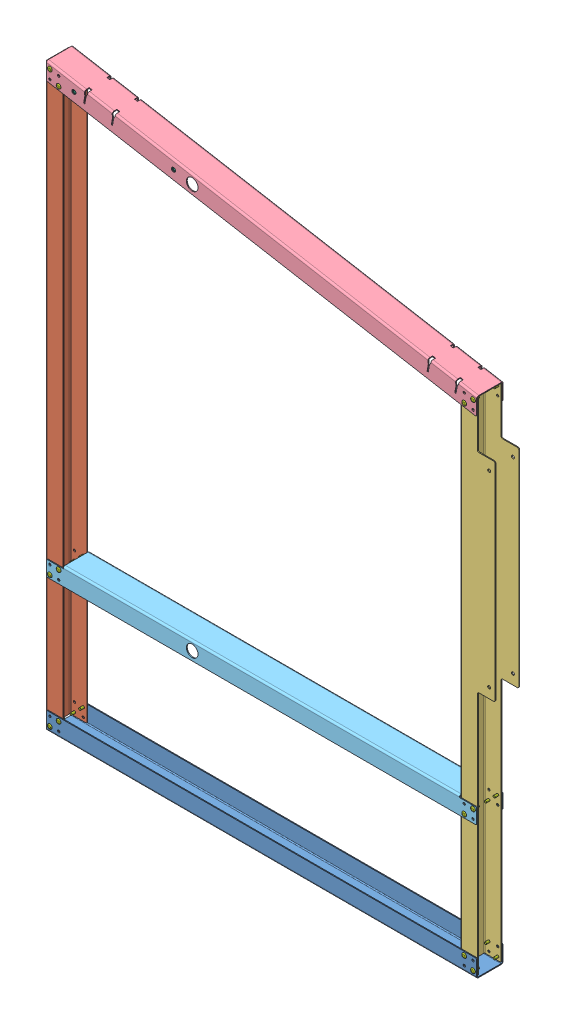
SolidWorks assembly GE-22001, configuration Default. Lengths in mm.
Overall size (976.07 1257.64 60.35).
33 component instances, 7 part files, 66 mates.
Components (placement in the parent):
- GE-22001-01-1: GE-22001-01 [Default] at origin size (932.18 38.1 57.15)
- GE-22001-02-1: GE-22001-02 [Default] at (-469.9 626.8796 0) x (0 0 1) z (-1 0 0) size (53.36 1249.93 38.1)
- GE-22001-03-2: GE-22001-03 [Default] at (427.99 548.0126 0) x (0 0 1) z (-1 0 0) size (53.36 1092.2 76.2)
- GE-22001-04-1: GE-22001-04 [Default] at (0.8773 1173.5467 0) x (0 0 -1) z (0.173648 0.984808 0) size (57.15 952.05 38.1)
- GE-22001-05-1: GE-22001-05 [Default] at (0 322.5952 0) x (1 0 0) z (0 0 -1) size (932.18 38.1 57.15)
- pem_clinchnut_.25_20_.054-1: pem_clinchnut_.25_20_.054 [Default] at (-190.6532 1187.9748 27.3634) x (0 0 -1) z (1 0 0) size (5.69 11.18 11.18)
- pem_clinchnut_.25_20_.054-2: pem_clinchnut_.25_20_.054 [Default] at (-406.4 1226.0168 27.3634) x (0 0 -1) z (0.987351 0.158553 0) size (5.69 11.18 11.18)
- pem_clinchnut_.25_20_.054-4: pem_clinchnut_.25_20_.054 [Default] at (-190.6532 1187.9748 -27.3634) x (0 0 1) z (-0.959125 0.282984 0) size (5.69 11.18 11.18)
- pem_clinchnut_.25_20_.054-6: pem_clinchnut_.25_20_.054 [Default] at (-406.4 1226.0168 -27.3634) x (0 0 1) z (-0.928571 0.371154 0) size (5.69 11.18 11.18)
- rivet_.1875_.126-.25-1: rivet_.1875_.126-.25 [Default] at (458.47 9.5326 28.575) size (10.01 10.01 13.03)
- rivet_.1875_.126-.25-2: rivet_.1875_.126-.25 [Default] at (439.42 28.5826 28.575) x (0.987351 0.158553 0) z (0 0 1) size (10.01 10.01 13.03)
- rivet_.1875_.126-.25-4: rivet_.1875_.126-.25 [Default] at (-458.47 9.5326 28.575) x (0.959125 0.282984 0) z (0 0 1) size (10.01 10.01 13.03)
- rivet_.1875_.126-.25-6: rivet_.1875_.126-.25 [Default] at (-439.42 28.5826 28.575) x (0.928571 0.371154 0) z (0 0 1) size (10.01 10.01 13.03)
- rivet_.1875_.126-.25-8: rivet_.1875_.126-.25 [Default] at (-458.47 294.0126 28.575) x (0.642788 0.766044 0) z (0 0 1) size (10.01 10.01 13.03)
- rivet_.1875_.126-.25-10: rivet_.1875_.126-.25 [Default] at (-439.42 313.0626 28.575) x (0.766044 0.642788 0) z (0 0 1) size (10.01 10.01 13.03)
- rivet_.1875_.126-.25-12: rivet_.1875_.126-.25 [Default] at (-458.47 1242.9356 28.575) x (0.919615 0.39282 0) z (0 0 1) size (10.01 10.01 13.03)
- rivet_.1875_.126-.25-14: rivet_.1875_.126-.25 [Default] at (-439.42 1220.2327 28.575) x (0.952324 0.305088 0) z (0 0 1) size (10.01 10.01 13.03)
- rivet_.1875_.126-.25-16: rivet_.1875_.126-.25 [Default] at (439.5161 1065.2526 28.575) x (0.985697 0.168526 0) z (0 0 1) size (10.01 10.01 13.03)
- rivet_.1875_.126-.25-18: rivet_.1875_.126-.25 [Default] at (458.5661 1081.2374 28.575) size (10.01 10.01 13.03)
- rivet_.1875_.126-.25-20: rivet_.1875_.126-.25 [Default] at (439.42 294.0126 28.575) x (0.984808 -0.173648 0) z (0 0 1) size (10.01 10.01 13.03)
- rivet_.1875_.126-.25-22: rivet_.1875_.126-.25 [Default] at (458.47 313.0626 28.575) x (0.939693 -0.34202 0) z (0 0 1) size (10.01 10.01 13.03)
- rivet_.1875_.126-.25-24: rivet_.1875_.126-.25 [Default] at (439.42 294.0126 -28.575) x (-0.866025 -0.5 0) z (0 0 -1) size (10.01 10.01 13.03)
- rivet_.1875_.126-.25-26: rivet_.1875_.126-.25 [Default] at (458.47 313.0626 -28.575) x (-0.766044 -0.642788 0) z (0 0 -1) size (10.01 10.01 13.03)
- rivet_.1875_.126-.25-28: rivet_.1875_.126-.25 [Default] at (458.47 9.5326 -28.575) x (-0.906989 -0.421154 0) z (0 0 -1) size (10.01 10.01 13.03)
- rivet_.1875_.126-.25-30: rivet_.1875_.126-.25 [Default] at (439.42 28.5826 -28.575) x (-0.928571 -0.371154 0) z (0 0 -1) size (10.01 10.01 13.03)
- rivet_.1875_.126-.25-32: rivet_.1875_.126-.25 [Default] at (-439.42 28.5826 -28.575) x (-0.959125 -0.282984 0) z (0 0 -1) size (10.01 10.01 13.03)
- rivet_.1875_.126-.25-34: rivet_.1875_.126-.25 [Default] at (-458.47 9.5326 -28.575) x (-0.987351 -0.158553 0) z (0 0 -1) size (10.01 10.01 13.03)
- rivet_.1875_.126-.25-36: rivet_.1875_.126-.25 [Default] at (-458.47 294.0126 -28.575) x (-0.923728 -0.383049 0) z (0 0 -1) size (10.01 10.01 13.03)
- rivet_.1875_.126-.25-38: rivet_.1875_.126-.25 [Default] at (-439.42 313.0626 -28.575) x (0.173648 -0.984808 0) z (0 0 -1) size (10.01 10.01 13.03)
- rivet_.1875_.126-.25-40: rivet_.1875_.126-.25 [Default] at (-439.42 1220.2327 -28.575) x (-0.916631 0.399735 0) z (0 0 -1) size (10.01 10.01 13.03)
- rivet_.1875_.126-.25-42: rivet_.1875_.126-.25 [Default] at (-458.47 1242.9356 -28.575) x (-0.785714 0.61859 0) z (0 0 -1) size (10.01 10.01 13.03)
- rivet_.1875_.126-.25-44: rivet_.1875_.126-.25 [Default] at (439.5161 1065.2526 -28.575) x (-0.572252 0.820078 0) z (0 0 -1) size (10.01 10.01 13.03)
- rivet_.1875_.126-.25-46: rivet_.1875_.126-.25 [Default] at (458.5661 1081.2374 -28.575) x (-0.266647 0.963794 0) z (0 0 -1) size (10.01 10.01 13.03)
Mates (geometry in assembly coordinates):
- Coincident2: coincident anti-aligned: plane of SideFrame5-01-1 through (0 0 26.6776) normal (0 0 -1); plane of SideFrame5-02A-1 through (-469.9 626.8796 26.6776) normal (0 0 1)
- Concentric3: concentric anti-aligned: cylinder of SideFrame5-01-1 through (-458.47 9.5326 -28.575) axis (0 0 1) radius 2.4638; cylinder of SideFrame5-02A-1 through (-458.47 9.5326 26.6776) axis (0 0 -1) radius 2.4638
- Concentric4: concentric anti-aligned: cylinder of SideFrame5-01-1 through (-458.47 28.5826 -28.575) axis (0 0 1) radius 2.4638; cylinder of SideFrame5-02A-1 through (-458.47 28.5826 26.6776) axis (0 0 -1) radius 2.4638
- Coincident4: coincident anti-aligned: plane of SideFrame5-02A-1 through (-469.9 626.8796 26.6776) normal (0 0 1); plane of GE-22001-04-1 through (0.8773 1173.5467 26.6776) normal (0 0 -1)
- Concentric6: concentric anti-aligned: cylinder of SideFrame5-02A-1 through (-458.47 1242.9356 26.6776) axis (0 0 -1) radius 2.4638; cylinder of GE-22001-04-1 through (-458.47 1242.9356 -28.575) axis (0 0 1) radius 2.4638
- Concentric7: concentric anti-aligned: cylinder of SideFrame5-02A-1 through (-458.47 1223.5918 26.6776) axis (0 0 -1) radius 2.4638; cylinder of GE-22001-04-1 through (-458.47 1223.5918 -28.575) axis (0 0 1) radius 2.4638
- Coincident5: coincident anti-aligned: plane of SideFrame5-02A-1 through (-469.9 626.8796 26.6776) normal (0 0 1); plane of SideFrame5-05-1 through (0 322.5952 26.6776) normal (0 0 -1)
- Coincident6: coincident anti-aligned: plane of SideFrame5-01-1 through (0 0 26.6776) normal (0 0 -1); plane of SideFrame5-03-2 through (469.265 532.1376 26.6776) normal (0 0 1)
- Concentric8: concentric anti-aligned: cylinder of SideFrame5-01-1 through (439.42 28.5826 -28.575) axis (0 0 1) radius 2.4638; cylinder of SideFrame5-03-2 through (439.42 28.5826 26.6776) axis (0 0 -1) radius 2.4638
- Concentric9: concentric anti-aligned: cylinder of SideFrame5-01-1 through (458.47 28.5826 -28.575) axis (0 0 1) radius 2.4638; cylinder of SideFrame5-03-2 through (458.47 28.5826 26.6776) axis (0 0 -1) radius 2.4638
- Concentric10: concentric anti-aligned: cylinder of GE-22001-04-1 through (-190.6532 1187.9748 28.575) axis (0 0 1) radius 4.3656; cylinder of pem_clinchnut_.25_20_.054-1 through (-190.6532 1187.9748 27.2052) axis (0 0 -1) radius 4.3561
- Coincident7: coincident anti-aligned: plane of GE-22001-04-1 through (0.8773 1173.5467 26.6776) normal (0 0 -1); plane of pem_clinchnut_.25_20_.054-1 through (-190.6532 1187.9748 26.6776) normal (0 0 1)
- Concentric11: concentric anti-aligned: cylinder of GE-22001-04-1 through (-406.4 1226.0168 28.575) axis (0 0 1) radius 4.3656; cylinder of pem_clinchnut_.25_20_.054-2 through (-406.4 1226.0168 27.2052) axis (0 0 -1) radius 4.3561
- Coincident8: coincident anti-aligned: plane of GE-22001-04-1 through (0.8773 1173.5467 26.6776) normal (0 0 -1); plane of pem_clinchnut_.25_20_.054-2 through (-406.4 1226.0168 26.6776) normal (0 0 1)
- Concentric12: concentric aligned: cylinder of GE-22001-04-1 through (-190.6532 1187.9748 28.575) axis (0 0 1) radius 4.3656; cylinder of pem_clinchnut_.25_20_.054-4 through (-190.6532 1187.9748 -27.2052) axis (0 0 1) radius 4.3561
- Coincident9: coincident anti-aligned: plane of GE-22001-04-1 through (0.8773 1173.5467 -26.6776) normal (0 0 1); plane of pem_clinchnut_.25_20_.054-4 through (-190.6532 1187.9748 -26.6776) normal (0 0 -1)
- Concentric13: concentric aligned: cylinder of GE-22001-04-1 through (-406.4 1226.0168 28.575) axis (0 0 1) radius 4.3656; cylinder of pem_clinchnut_.25_20_.054-6 through (-406.4 1226.0168 -27.2052) axis (0 0 1) radius 4.3561
- Coincident10: coincident anti-aligned: plane of GE-22001-04-1 through (0.8773 1173.5467 -26.6776) normal (0 0 1); plane of pem_clinchnut_.25_20_.054-6 through (-406.4 1226.0168 -26.6776) normal (0 0 -1)
- Concentric14: concentric aligned: cylinder of SideFrame5-01-1 through (458.47 9.5326 -28.575) axis (0 0 1) radius 2.4638; cylinder of rivet_.1875_.126-.25-1 through (458.47 9.5326 17.145) axis (0 0 1) radius 2.3813
- Coincident11: coincident anti-aligned: plane of SideFrame5-01-1 through (0 0 28.575) normal (0 0 1); plane of rivet_.1875_.126-.25-1 through (458.47 9.5326 28.575) normal (0 0 -1)
- Concentric15: concentric aligned: cylinder of SideFrame5-01-1 through (439.42 28.5826 -28.575) axis (0 0 1) radius 2.4638; cylinder of rivet_.1875_.126-.25-2 through (439.42 28.5826 17.145) axis (0 0 1) radius 2.3813
- Coincident12: coincident anti-aligned: plane of SideFrame5-01-1 through (0 0 28.575) normal (0 0 1); plane of rivet_.1875_.126-.25-2 through (439.42 28.5826 28.575) normal (0 0 -1)
- Concentric16: concentric aligned: cylinder of SideFrame5-01-1 through (-458.47 9.5326 -28.575) axis (0 0 1) radius 2.4638; cylinder of rivet_.1875_.126-.25-4 through (-458.47 9.5326 17.145) axis (0 0 1) radius 2.3813
- Coincident13: coincident anti-aligned: plane of SideFrame5-01-1 through (0 0 28.575) normal (0 0 1); plane of rivet_.1875_.126-.25-4 through (-458.47 9.5326 28.575) normal (0 0 -1)
- Concentric17: concentric aligned: cylinder of SideFrame5-01-1 through (-439.42 28.5826 -28.575) axis (0 0 1) radius 2.4638; cylinder of rivet_.1875_.126-.25-6 through (-439.42 28.5826 17.145) axis (0 0 1) radius 2.3813
- Coincident14: coincident anti-aligned: plane of SideFrame5-01-1 through (0 0 28.575) normal (0 0 1); plane of rivet_.1875_.126-.25-6 through (-439.42 28.5826 28.575) normal (0 0 -1)
- Concentric18: concentric anti-aligned: cylinder of SideFrame5-05-1 through (-458.47 294.0126 28.575) axis (0 0 -1) radius 2.4638; cylinder of rivet_.1875_.126-.25-8 through (-458.47 294.0126 17.145) axis (0 0 1) radius 2.3813
- Coincident15: coincident anti-aligned: plane of SideFrame5-05-1 through (0 322.5952 28.575) normal (0 0 1); plane of rivet_.1875_.126-.25-8 through (-458.47 294.0126 28.575) normal (0 0 -1)
- Concentric19: concentric anti-aligned: cylinder of SideFrame5-05-1 through (-439.42 313.0626 28.575) axis (0 0 -1) radius 2.4638; cylinder of rivet_.1875_.126-.25-10 through (-439.42 313.0626 17.145) axis (0 0 1) radius 2.3813
- Coincident16: coincident anti-aligned: plane of SideFrame5-05-1 through (0 322.5952 28.575) normal (0 0 1); plane of rivet_.1875_.126-.25-10 through (-439.42 313.0626 28.575) normal (0 0 -1)
- Concentric20: concentric aligned: cylinder of GE-22001-04-1 through (-458.47 1242.9356 -28.575) axis (0 0 1) radius 2.4638; cylinder of rivet_.1875_.126-.25-12 through (-458.47 1242.9356 17.145) axis (0 0 1) radius 2.3813
- Coincident17: coincident anti-aligned: plane of GE-22001-04-1 through (0.8773 1173.5467 28.575) normal (0 0 1); plane of rivet_.1875_.126-.25-12 through (-458.47 1242.9356 28.575) normal (0 0 -1)
- Concentric21: concentric aligned: cylinder of GE-22001-04-1 through (-439.42 1220.2327 -28.575) axis (0 0 1) radius 2.4638; cylinder of rivet_.1875_.126-.25-14 through (-439.42 1220.2327 17.145) axis (0 0 1) radius 2.3813
- Coincident18: coincident anti-aligned: plane of GE-22001-04-1 through (0.8773 1173.5467 28.575) normal (0 0 1); plane of rivet_.1875_.126-.25-14 through (-439.42 1220.2327 28.575) normal (0 0 -1)
- Concentric22: concentric aligned: cylinder of GE-22001-04-1 through (439.5161 1065.2526 -28.575) axis (0 0 1) radius 2.4638; cylinder of rivet_.1875_.126-.25-16 through (439.5161 1065.2526 17.145) axis (0 0 1) radius 2.3813
- Coincident19: coincident anti-aligned: plane of GE-22001-04-1 through (0.8773 1173.5467 28.575) normal (0 0 1); plane of rivet_.1875_.126-.25-16 through (439.5161 1065.2526 28.575) normal (0 0 -1)
- Concentric23: concentric aligned: cylinder of GE-22001-04-1 through (458.5661 1081.2374 -28.575) axis (0 0 1) radius 2.4638; cylinder of rivet_.1875_.126-.25-18 through (458.5661 1081.2374 17.145) axis (0 0 1) radius 2.3813
- Coincident20: coincident anti-aligned: plane of GE-22001-04-1 through (0.8773 1173.5467 28.575) normal (0 0 1); plane of rivet_.1875_.126-.25-18 through (458.5661 1081.2374 28.575) normal (0 0 -1)
- Concentric24: concentric anti-aligned: cylinder of SideFrame5-05-1 through (439.42 294.0126 28.575) axis (0 0 -1) radius 2.4638; cylinder of rivet_.1875_.126-.25-20 through (439.42 294.0126 17.145) axis (0 0 1) radius 2.3813
- Coincident21: coincident anti-aligned: plane of SideFrame5-05-1 through (0 322.5952 28.575) normal (0 0 1); plane of rivet_.1875_.126-.25-20 through (439.42 294.0126 28.575) normal (0 0 -1)
- Concentric25: concentric anti-aligned: cylinder of SideFrame5-05-1 through (458.47 313.0626 28.575) axis (0 0 -1) radius 2.4638; cylinder of rivet_.1875_.126-.25-22 through (458.47 313.0626 17.145) axis (0 0 1) radius 2.3813
- Coincident22: coincident anti-aligned: plane of SideFrame5-05-1 through (0 322.5952 28.575) normal (0 0 1); plane of rivet_.1875_.126-.25-22 through (458.47 313.0626 28.575) normal (0 0 -1)
- Concentric26: concentric aligned: cylinder of SideFrame5-05-1 through (439.42 294.0126 28.575) axis (0 0 -1) radius 2.4638; cylinder of rivet_.1875_.126-.25-24 through (439.42 294.0126 -17.145) axis (0 0 -1) radius 2.3813
- Coincident23: coincident anti-aligned: plane of SideFrame5-05-1 through (0 322.5952 -28.575) normal (0 0 -1); plane of rivet_.1875_.126-.25-24 through (439.42 294.0126 -28.575) normal (0 0 1)
- Concentric27: concentric aligned: cylinder of SideFrame5-05-1 through (458.47 313.0626 28.575) axis (0 0 -1) radius 2.4638; cylinder of rivet_.1875_.126-.25-26 through (458.47 313.0626 -17.145) axis (0 0 -1) radius 2.3813
- Coincident24: coincident anti-aligned: plane of SideFrame5-05-1 through (0 322.5952 -28.575) normal (0 0 -1); plane of rivet_.1875_.126-.25-26 through (458.47 313.0626 -28.575) normal (0 0 1)
- Concentric28: concentric anti-aligned: cylinder of SideFrame5-01-1 through (458.47 9.5326 -28.575) axis (0 0 1) radius 2.4638; cylinder of rivet_.1875_.126-.25-28 through (458.47 9.5326 -17.145) axis (0 0 -1) radius 2.3813
- Coincident25: coincident anti-aligned: plane of SideFrame5-01-1 through (0 0 -28.575) normal (0 0 -1); plane of rivet_.1875_.126-.25-28 through (458.47 9.5326 -28.575) normal (0 0 1)
- Concentric29: concentric anti-aligned: cylinder of SideFrame5-01-1 through (439.42 28.5826 -28.575) axis (0 0 1) radius 2.4638; cylinder of rivet_.1875_.126-.25-30 through (439.42 28.5826 -17.145) axis (0 0 -1) radius 2.3813
- Coincident26: coincident anti-aligned: plane of SideFrame5-01-1 through (0 0 -28.575) normal (0 0 -1); plane of rivet_.1875_.126-.25-30 through (439.42 28.5826 -28.575) normal (0 0 1)
- Concentric30: concentric anti-aligned: cylinder of SideFrame5-01-1 through (-439.42 28.5826 -28.575) axis (0 0 1) radius 2.4638; cylinder of rivet_.1875_.126-.25-32 through (-439.42 28.5826 -17.145) axis (0 0 -1) radius 2.3813
- Coincident27: coincident anti-aligned: plane of SideFrame5-01-1 through (0 0 -28.575) normal (0 0 -1); plane of rivet_.1875_.126-.25-32 through (-439.42 28.5826 -28.575) normal (0 0 1)
- Concentric31: concentric anti-aligned: cylinder of SideFrame5-01-1 through (-458.47 9.5326 -28.575) axis (0 0 1) radius 2.4638; cylinder of rivet_.1875_.126-.25-34 through (-458.47 9.5326 -17.145) axis (0 0 -1) radius 2.3813
- Coincident28: coincident anti-aligned: plane of SideFrame5-01-1 through (0 0 -28.575) normal (0 0 -1); plane of rivet_.1875_.126-.25-34 through (-458.47 9.5326 -28.575) normal (0 0 1)
- Concentric32: concentric aligned: cylinder of SideFrame5-05-1 through (-458.47 294.0126 28.575) axis (0 0 -1) radius 2.4638; cylinder of rivet_.1875_.126-.25-36 through (-458.47 294.0126 -17.145) axis (0 0 -1) radius 2.3813
- Coincident29: coincident anti-aligned: plane of SideFrame5-05-1 through (0 322.5952 -28.575) normal (0 0 -1); plane of rivet_.1875_.126-.25-36 through (-458.47 294.0126 -28.575) normal (0 0 1)
- Concentric33: concentric aligned: cylinder of SideFrame5-05-1 through (-439.42 313.0626 28.575) axis (0 0 -1) radius 2.4638; cylinder of rivet_.1875_.126-.25-38 through (-439.42 313.0626 -17.145) axis (0 0 -1) radius 2.3813
- Coincident30: coincident anti-aligned: plane of SideFrame5-05-1 through (0 322.5952 -28.575) normal (0 0 -1); plane of rivet_.1875_.126-.25-38 through (-439.42 313.0626 -28.575) normal (0 0 1)
- Concentric34: concentric anti-aligned: cylinder of GE-22001-04-1 through (-439.42 1220.2327 -28.575) axis (0 0 1) radius 2.4638; cylinder of rivet_.1875_.126-.25-40 through (-439.42 1220.2327 -17.145) axis (0 0 -1) radius 2.3813
- Coincident31: coincident anti-aligned: plane of GE-22001-04-1 through (0.8773 1173.5467 -28.575) normal (0 0 -1); plane of rivet_.1875_.126-.25-40 through (-439.42 1220.2327 -28.575) normal (0 0 1)
- Concentric35: concentric anti-aligned: cylinder of GE-22001-04-1 through (-458.47 1242.9356 -28.575) axis (0 0 1) radius 2.4638; cylinder of rivet_.1875_.126-.25-42 through (-458.47 1242.9356 -17.145) axis (0 0 -1) radius 2.3813
- Coincident32: coincident anti-aligned: plane of GE-22001-04-1 through (0.8773 1173.5467 -28.575) normal (0 0 -1); plane of rivet_.1875_.126-.25-42 through (-458.47 1242.9356 -28.575) normal (0 0 1)
- Concentric36: concentric anti-aligned: cylinder of GE-22001-04-1 through (439.5161 1065.2526 -28.575) axis (0 0 1) radius 2.4638; cylinder of rivet_.1875_.126-.25-44 through (439.5161 1065.2526 -17.145) axis (0 0 -1) radius 2.3813
- Coincident33: coincident anti-aligned: plane of GE-22001-04-1 through (0.8773 1173.5467 -28.575) normal (0 0 -1); plane of rivet_.1875_.126-.25-44 through (439.5161 1065.2526 -28.575) normal (0 0 1)
- Concentric37: concentric anti-aligned: cylinder of GE-22001-04-1 through (458.5661 1081.2374 -28.575) axis (0 0 1) radius 2.4638; cylinder of rivet_.1875_.126-.25-46 through (458.5661 1081.2374 -17.145) axis (0 0 -1) radius 2.3813
- Coincident34: coincident anti-aligned: plane of GE-22001-04-1 through (0.8773 1173.5467 -28.575) normal (0 0 -1); plane of rivet_.1875_.126-.25-46 through (458.5661 1081.2374 -28.575) normal (0 0 1)
